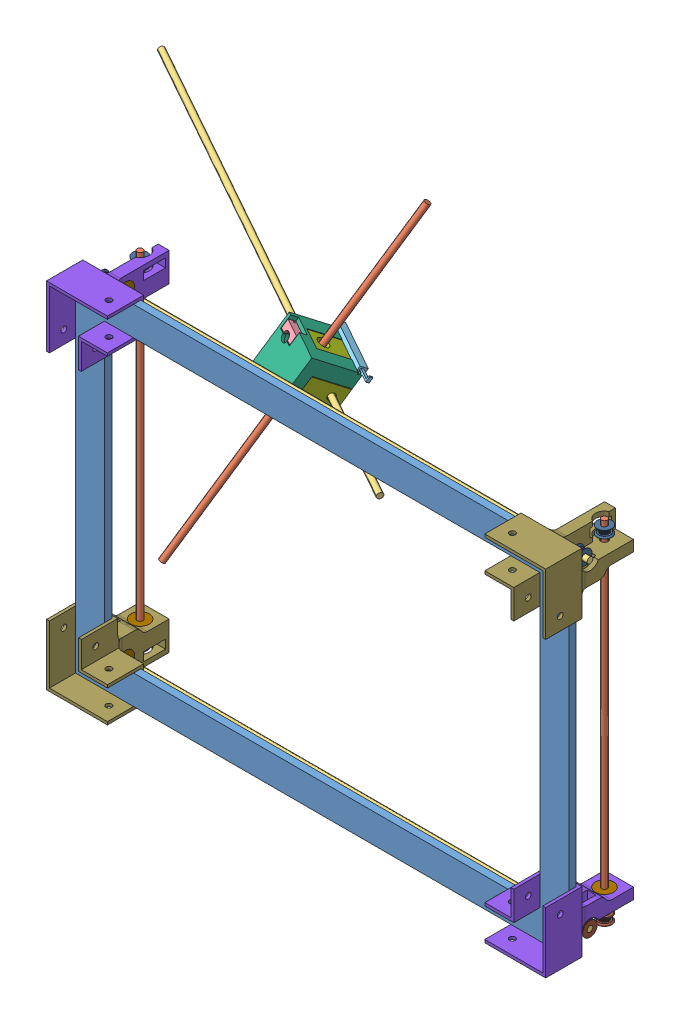
SolidWorks assembly Assemblage_XY, configuration Défaut. Lengths in mm.
Overall size (905.47 614.07 376.87).
36 component instances, 12 part files, 54 mates.
Components (placement in the parent):
- Cadre_XY-1: Cadre_XY [Défaut] at (379.0068 -247.2078 675) size (680 480 10)
- AXE_8X480-1: AXE_8X480 [Défaut] at (359.0068 232.7922 616) x (0.999993 0 -0.00366) z (0 -1 0) size (8 8 480)
- AXE_8X480-2: AXE_8X480 [Défaut] at (-280.9932 -247.2078 616) x (0.987721 0 0.156231) z (0 1 0) size (8 8 480)
- AXE_8X680-1: AXE_8X680 [Défaut] at (379.0068 212.7922 656) x (0 0.013067 0.999915) z (-1 0 0) size (8 8 680)
- AXE_8X680-2: AXE_8X680 [Défaut] at (379.0068 -227.2078 656) x (0 0.106795 0.994281) z (-1 0 0) size (8 8 680)
- AXE_8X480-3: AXE_8X480 [Défaut] at (-13.625 359.5615 487.1744) x (0.918438 -0.176427 0.354041) z (-0.328403 -0.839013 0.43383) size (8 8 480)
- AXE_8X680-3: AXE_8X680 [Défaut] at (-519.2906 219.9196 348.3962) x (-0.222016 -0.956255 0.190485) z (0.887884 -0.117538 0.4448) size (8 8 680)
- P3DMIPC-Tête_complete-1: P3DMIPC-Tête_complete [Défaut] at (-120.2935 186.5205 555.0197) x (0.328403 0.839013 -0.43383) z (0.887884 -0.117538 0.4448) size (84 69 89)
  - P3DMIPC-Clip_Buse_E3D-1: P3DMIPC-Clip_Buse_E3D [Défaut] at (17.0518 23.4109 40.0035) x (1 0 0) z (0 1 0) size (12 26 10)
  - P3DMIPC-Clip_tête-1: P3DMIPC-Clip_tête [Défaut] at (26.9018 -25.0891 4.5597) x (1 0 0) z (0 -1 0) size (84 89 10.5)
  - P3DMIPC-Porte_Buse_E3DX1-1: P3DMIPC-Porte_Buse_E3DX1 [Défaut] at (22.03 33.4019 79.1927) x (0 0 1) z (0 -1 0) size (70 70 64)
  - P3DMIPC-Chariot-1: P3DMIPC-Chariot [Défaut] at (-48.37 -30.5981 79.1927) size (70 50 70)
- Angle_magique_G-1: Angle_magique_G [Défaut] at (379.0068 -247.2078 675) x (-1 0 0) z (0 0 -1) size (84.54 84.54 125)
- F608ZZ-1: F608ZZ [Défaut] at (346.0068 -227.2078 656) x (0 0 1) z (-1 0 0) size (25 25 7)
- Angle_magique_G-4: Angle_magique_G [Défaut] at (-300.9932 232.7922 675) x (1 0 0) z (0 0 -1) size (84.54 84.54 125)
- pulley_gt2_3mm_20t-10: pulley_gt2_3mm_20t [Défaut] at (-280.9932 214.0422 616) x (0.106795 0 0.994281) z (0 1 0) size (20 20 10.5)
- pulley_gt2_3mm_20t-11: pulley_gt2_3mm_20t [Défaut] at (-282.2432 212.7922 656) x (0 0.106795 0.994281) z (-1 0 0) size (20 20 10.5)
- pulley_gt2_3mm_20t-12: pulley_gt2_3mm_20t [Défaut] at (-280.9932 -240.9578 616) x (-0.771074 0 0.636745) z (0 1 0) size (20 20 10.5)
- pulley_gt2_3mm_20t-13: pulley_gt2_3mm_20t [Défaut] at (-282.2432 -227.2078 656) x (0 0.106795 0.994281) z (-1 0 0) size (20 20 10.5)
- pulley_gt2_3mm_20t-15: pulley_gt2_3mm_20t [Défaut] at (359.0068 226.5422 616) x (-0.106795 0 0.994281) z (0 -1 0) size (20 20 10.5)
- pulley_gt2_3mm_20t-16: pulley_gt2_3mm_20t [Défaut] at (372.7568 212.7922 656) x (0 0.106795 0.994281) z (-1 0 0) size (20 20 10.5)
- F608ZZ-2: F608ZZ [Défaut] at (-280.9932 199.7922 616) x (0 0 1) z (0 -1 0) size (25 25 7)
- F608ZZ-3: F608ZZ [Défaut] at (-267.9932 212.7922 656) x (0 -0.924225 -0.381849) z (1 0 0) size (25 25 7)
- F608ZZ-4: F608ZZ [Défaut] at (-280.9932 -214.2078 616) x (0 0 1) z (0 1 0) size (25 25 7)
- F608ZZ-5: F608ZZ [Défaut] at (-267.9932 -227.2078 656) x (0 -0.924225 -0.381849) z (1 0 0) size (25 25 7)
- F608ZZ-6: F608ZZ [Défaut] at (359.0068 -214.2078 616) x (0 0 1) z (0 1 0) size (25 25 7)
- F608ZZ-7: F608ZZ [Défaut] at (359.0068 199.7922 616) x (0 0 1) z (0 -1 0) size (25 25 7)
- F608ZZ-8: F608ZZ [Défaut] at (346.0068 212.7922 656) x (0 0 1) z (-1 0 0) size (25 25 7)
- Doublepulley_gt2_3mm_20t-1: Doublepulley_gt2_3mm_20t [Défaut] at (372.5376 -232.3307 673.9631) x (0 0 -1) z (1 0 0) size (25.2 25.2 18.5)
  - pulley_light_gt2_3mm_20t-1: pulley_light_gt2_3mm_20t [Défaut] at (17.9631 5.1229 -13.0308) size (20 20 9.25)
  - pulley_light_gt2_3mm_20t-2: pulley_light_gt2_3mm_20t [Défaut] at (17.9631 5.1229 7.4692) x (-0.95107 -0.308976 0) z (0 0 -1) size (20 20 9.25)
- Doublepulley_gt2_3mm_20t-2: Doublepulley_gt2_3mm_20t [Défaut] at (376.8469 -235.177 621.5361) x (-0.837169 0 -0.546944) z (0 1 0) size (25.2 25.2 18.5)
  - pulley_light_gt2_3mm_20t-1: pulley_light_gt2_3mm_20t [Défaut] at (17.9631 5.1229 -13.0308) size (20 20 9.25)
  - pulley_light_gt2_3mm_20t-2: pulley_light_gt2_3mm_20t [Défaut] at (17.9631 5.1229 7.4692) x (-0.95107 -0.308976 0) z (0 0 -1) size (20 20 9.25)
- Angle_magique_D-1: Angle_magique_D [Défaut] at (-300.9932 -247.2078 675) x (0 1 0) z (0 0 -1) size (84.54 84.67 125)
- Angle_magique_D-2: Angle_magique_D [Défaut] at (379.0068 232.7922 675) x (0 -1 0) z (0 0 -1) size (84.54 84.67 125)
Mates (geometry in assembly coordinates):
- Coaxiale1: concentric anti-aligned: cylinder of AXE_8X680-3 through (84.4704 139.9935 650.86) axis (-0.887884 0.117538 -0.4448) radius 4; cylinder of P3DMIPC-Tête_complete-1/P3DMIPC-Chariot-1 through (-52.8962 158.1781 582.044) axis (0.887884 -0.117538 0.4448) radius 5
- Coaxiale2: concentric anti-aligned: cylinder of AXE_8X480-3 through (-171.2586 -43.1647 695.413) axis (0.328403 0.839013 -0.43383) radius 4; cylinder of P3DMIPC-Tête_complete-1/P3DMIPC-Chariot-1 through (-97.0451 146.4377 597.3748) axis (-0.328403 -0.839013 0.43383) radius 5
- Coïncidente14: coincident anti-aligned: plane of Cadre_XY-1 through (379.0068 -247.2078 675) normal (0 0 -1); plane of Angle_magique_G-1 through (379.0068 -247.2078 675) normal (0 0 1)
- Coïncidente15: coincident anti-aligned: plane of Cadre_XY-1 through (379.0068 -247.2078 685) normal (1 0 0); plane of Angle_magique_G-1 through (379.0068 -247.2078 721) normal (-1 0 0)
- Coïncidente16: coincident anti-aligned: plane of Cadre_XY-1 through (379.0068 -247.2078 685) normal (0 -1 0); plane of Angle_magique_G-1 through (299.0068 -247.2078 721) normal (0 1 0)
- Coaxiale15: concentric anti-aligned: cylinder of AXE_8X680-2 through (-300.9932 -227.2078 656) axis (1 0 0) radius 4; cylinder of Angle_magique_G-1 through (389.0068 -227.2078 656) axis (-1 0 0) radius 5
- Coïncidente18: coincident anti-aligned: plane of Angle_magique_G-1 through (346.0068 -227.2078 656) normal (-1 0 0); plane of F608ZZ-1 through (346.0068 -227.2078 656) normal (1 0 0)
- Coaxiale16: concentric anti-aligned: cylinder of Angle_magique_G-1 through (346.0068 -227.2078 656) axis (-1 0 0) radius 11; cylinder of F608ZZ-1 through (340.5068 -227.2078 656) axis (1 0 0) radius 11
- Coïncidente27: coincident anti-aligned: plane of Cadre_XY-1 through (379.0068 -247.2078 675) normal (0 0 -1); plane of Angle_magique_G-4 through (-300.9932 232.7922 675) normal (0 0 1)
- Coïncidente28: coincident anti-aligned: plane of Cadre_XY-1 through (379.0068 232.7922 685) normal (0 1 0); plane of Angle_magique_G-4 through (-220.9932 232.7922 721) normal (0 -1 0)
- Coïncidente29: coincident anti-aligned: plane of Cadre_XY-1 through (-300.9932 -247.2078 685) normal (-1 0 0); plane of Angle_magique_G-4 through (-300.9932 232.7922 721) normal (1 0 0)
- Coaxiale17: concentric anti-aligned: cylinder of AXE_8X680-1 through (-300.9932 212.7922 656) axis (1 0 0) radius 4; cylinder of pulley_gt2_3mm_20t-11 through (-282.2432 212.7922 656) axis (-1 0 0) radius 4
- Coaxiale18: concentric aligned: cylinder of AXE_8X680-1 through (-300.9932 212.7922 656) axis (1 0 0) radius 4; cylinder of Angle_magique_G-4 through (-310.9932 212.7922 656) axis (1 0 0) radius 5
- Coïncidente30: coincident aligned: plane of Cadre_XY-1 through (-300.9932 -247.2078 685) normal (-1 0 0); plane of AXE_8X680-1 through (-300.9932 212.7922 656) normal (-1 0 0)
- Distance2: distance = 7.25 mm anti-aligned: plane of pulley_gt2_3mm_20t-11 through (-283.2432 212.7922 656) normal (1 0 0); plane of Angle_magique_G-4 through (-275.9932 192.7922 621) normal (-1 0 0)
- Coaxiale19: concentric anti-aligned: cylinder of AXE_8X680-1 through (-300.9932 212.7922 656) axis (1 0 0) radius 4; cylinder of pulley_gt2_3mm_20t-16 through (388.9364 212.7922 656) axis (-1 0 0) radius 4
- Coaxiale20: concentric aligned: cylinder of AXE_8X480-1 through (359.0068 -247.2078 616) axis (0 1 0) radius 4; cylinder of Angle_magique_G-1 through (359.0068 -247.2078 616) axis (0 1 0) radius 5
- Coïncidente33: coincident aligned: plane of Cadre_XY-1 through (379.0068 -247.2078 685) normal (0 -1 0); circle of AXE_8X480-1
- Coaxiale22: concentric anti-aligned: cylinder of AXE_8X480-1 through (359.0068 -247.2078 616) axis (0 1 0) radius 4; cylinder of pulley_gt2_3mm_20t-15 through (359.0068 226.5422 616) axis (0 -1 0) radius 4
- Coaxiale23: concentric anti-aligned: cylinder of AXE_8X680-2 through (-300.9932 -227.2078 656) axis (1 0 0) radius 4; cylinder of pulley_gt2_3mm_20t-13 through (-282.2432 -227.2078 656) axis (-1 0 0) radius 4
- Coaxiale24: concentric aligned: cylinder of AXE_8X480-2 through (-280.9932 232.7922 616) axis (0 -1 0) radius 4; cylinder of Angle_magique_G-4 through (-280.9932 232.7923 616) axis (0 -1 0) radius 5
- Coaxiale25: concentric anti-aligned: cylinder of AXE_8X480-2 through (-280.9932 232.7922 616) axis (0 -1 0) radius 4; cylinder of pulley_gt2_3mm_20t-10 through (-280.9932 214.0422 616) axis (0 1 0) radius 4
- Coïncidente34: coincident aligned: plane of Cadre_XY-1 through (379.0068 232.7922 685) normal (0 1 0); plane of AXE_8X480-2 through (-280.9932 232.7922 616) normal (0 1 0)
- Distance4: distance = 7.25 mm anti-aligned: plane of pulley_gt2_3mm_20t-10 through (-280.9932 215.0422 616) normal (0 -1 0); plane of Angle_magique_G-4 through (-275.9932 207.7922 621) normal (0 1 0)
- Coaxiale26: concentric anti-aligned: cylinder of AXE_8X480-2 through (-280.9932 232.7922 616) axis (0 -1 0) radius 4; cylinder of pulley_gt2_3mm_20t-12 through (-280.9932 -240.9578 616) axis (0 1 0) radius 4
- Coïncidente36: coincident anti-aligned: plane of Angle_magique_G-4 through (-280.9932 199.7922 616) normal (0 -1 0); plane of F608ZZ-2 through (-280.9932 199.7922 616) normal (0 1 0)
- Coaxiale27: concentric anti-aligned: cylinder of Angle_magique_G-4 through (-280.9932 199.7922 616) axis (0 -1 0) radius 11; cylinder of F608ZZ-2 through (-280.9932 194.2922 616) axis (0 1 0) radius 11
- Coïncidente37: coincident anti-aligned: plane of Angle_magique_G-1 through (359.0068 -214.2078 616) normal (0 1 0); plane of F608ZZ-6 through (359.0068 -214.2078 616) normal (0 -1 0)
- Coaxiale28: concentric anti-aligned: cylinder of Angle_magique_G-1 through (359.0068 -214.2078 616) axis (0 1 0) radius 11; cylinder of F608ZZ-6 through (359.0068 -208.7078 616) axis (0 -1 0) radius 11
- Coïncidente38: coincident anti-aligned: plane of Angle_magique_G-4 through (-267.9932 212.7922 656) normal (1 0 0); plane of F608ZZ-3 through (-267.9932 212.7922 656) normal (-1 0 0)
- Coaxiale29: concentric anti-aligned: cylinder of Angle_magique_G-4 through (-267.9932 212.7922 656) axis (1 0 0) radius 11; cylinder of F608ZZ-3 through (-262.4932 212.7922 656) axis (-1 0 0) radius 11
- Distance7: distance = 6.5 mm anti-aligned: plane of Angle_magique_G-1 through (354.0068 -222.2078 621) normal (0 -1 0); plane of Doublepulley_gt2_3mm_20t-2/pulley_light_gt2_3mm_20t-2 through (359.0068 -228.7078 616) normal (0 1 0)
- Coaxiale31: concentric aligned: cylinder of AXE_8X480-1 through (359.0068 -247.2078 616) axis (0 1 0) radius 4; cylinder of Doublepulley_gt2_3mm_20t-2/pulley_light_gt2_3mm_20t-1 through (359.0068 -248.2078 616) axis (0 1 0) radius 4
- Distance8: distance = 6.5 mm anti-aligned: plane of Angle_magique_G-1 through (354.0068 -207.2078 621) normal (1 0 0); plane of Doublepulley_gt2_3mm_20t-1/pulley_light_gt2_3mm_20t-1 through (360.5068 -227.2078 656) normal (-1 0 0)
- Coaxiale32: concentric anti-aligned: cylinder of AXE_8X680-2 through (-300.9932 -227.2078 656) axis (1 0 0) radius 4; cylinder of Doublepulley_gt2_3mm_20t-1/pulley_light_gt2_3mm_20t-2 through (380.0068 -227.2078 656) axis (-1 0 0) radius 4
- Coïncidente43: coincident aligned: plane of Cadre_XY-1 through (379.0068 -247.2078 685) normal (1 0 0); plane of AXE_8X680-2 through (379.0068 -227.2078 656) normal (1 0 0)
- Coïncidente44: coincident anti-aligned: plane of Cadre_XY-1 through (379.0068 -247.2078 675) normal (0 0 -1); plane of Angle_magique_D-1 through (-300.9932 -247.2078 675) normal (0 0 1)
- Coïncidente45: coincident anti-aligned: plane of Cadre_XY-1 through (379.0068 -247.2078 685) normal (0 -1 0); plane of Angle_magique_D-1 through (-300.9932 -247.2078 721) normal (0 1 0)
- Coïncidente46: coincident anti-aligned: plane of Cadre_XY-1 through (-300.9932 -247.2078 685) normal (-1 0 0); plane of Angle_magique_D-1 through (-300.9932 -167.2078 721) normal (1 0 0)
- Distance9: distance = 7.25 mm anti-aligned: plane of pulley_gt2_3mm_20t-13 through (-283.2432 -227.2078 656) normal (1 0 0); plane of Angle_magique_D-1 through (-275.9932 -222.2078 621) normal (-1 0 0)
- Distance10: distance = 7.25 mm anti-aligned: plane of Angle_magique_D-1 through (-260.9932 -222.2078 621) normal (0 -1 0); plane of pulley_gt2_3mm_20t-12 through (-280.9932 -229.4578 616) normal (0 1 0)
- Coïncidente49: coincident anti-aligned: plane of F608ZZ-5 through (-267.9932 -227.2078 656) normal (-1 0 0); plane of Angle_magique_D-1 through (-267.9932 -227.2078 656) normal (1 0 0)
- Coaxiale33: concentric anti-aligned: cylinder of F608ZZ-5 through (-262.4932 -227.2078 656) axis (-1 0 0) radius 11; cylinder of Angle_magique_D-1 through (-267.9932 -227.2078 656) axis (1 0 0) radius 11
- Coïncidente50: coincident anti-aligned: plane of F608ZZ-4 through (-280.9932 -214.2078 616) normal (0 -1 0); plane of Angle_magique_D-1 through (-280.9932 -214.2078 616) normal (0 1 0)
- Coaxiale34: concentric anti-aligned: cylinder of F608ZZ-4 through (-280.9932 -208.7078 616) axis (0 -1 0) radius 11; cylinder of Angle_magique_D-1 through (-280.9932 -214.2078 616) axis (0 1 0) radius 11
- Coïncidente51: coincident anti-aligned: plane of Cadre_XY-1 through (379.0068 -247.2078 675) normal (0 0 -1); plane of Angle_magique_D-2 through (379.0068 232.7922 675) normal (0 0 1)
- Coïncidente52: coincident anti-aligned: plane of Cadre_XY-1 through (379.0068 232.7922 685) normal (0 1 0); plane of Angle_magique_D-2 through (379.0068 232.7922 721) normal (0 -1 0)
- Coïncidente53: coincident anti-aligned: plane of Cadre_XY-1 through (379.0068 -247.2078 685) normal (1 0 0); plane of Angle_magique_D-2 through (379.0068 152.7922 721) normal (-1 0 0)
- Distance11: distance = 7.25 mm anti-aligned: plane of pulley_gt2_3mm_20t-15 through (359.0068 215.0422 616) normal (0 -1 0); plane of Angle_magique_D-2 through (339.0068 207.7922 621) normal (0 1 0)
- Distance12: distance = 7.25 mm anti-aligned: plane of Angle_magique_D-2 through (354.0068 207.7922 621) normal (1 0 0); plane of pulley_gt2_3mm_20t-16 through (361.2568 212.7922 656) normal (-1 0 0)
- Coaxiale35: concentric: cylinder of F608ZZ-8 through (340.5068 212.7922 656) axis (1 0 0) radius 11; cylinder of Angle_magique_D-2 through (346.0068 212.7922 656) axis (-1 0 0) radius 11
- Coïncidente57: coincident anti-aligned: plane of F608ZZ-8 through (346.0068 212.7922 656) normal (1 0 0); plane of Angle_magique_D-2 through (346.0068 212.7922 656) normal (-1 0 0)
- Coaxiale36: concentric: cylinder of F608ZZ-7 through (359.0068 194.2922 616) axis (0 1 0) radius 11; cylinder of Angle_magique_D-2 through (359.0068 199.7922 616) axis (0 -1 0) radius 11
- Coïncidente58: coincident anti-aligned: plane of F608ZZ-7 through (359.0068 199.7922 616) normal (0 1 0); plane of Angle_magique_D-2 through (359.0068 199.7922 616) normal (0 -1 0)
